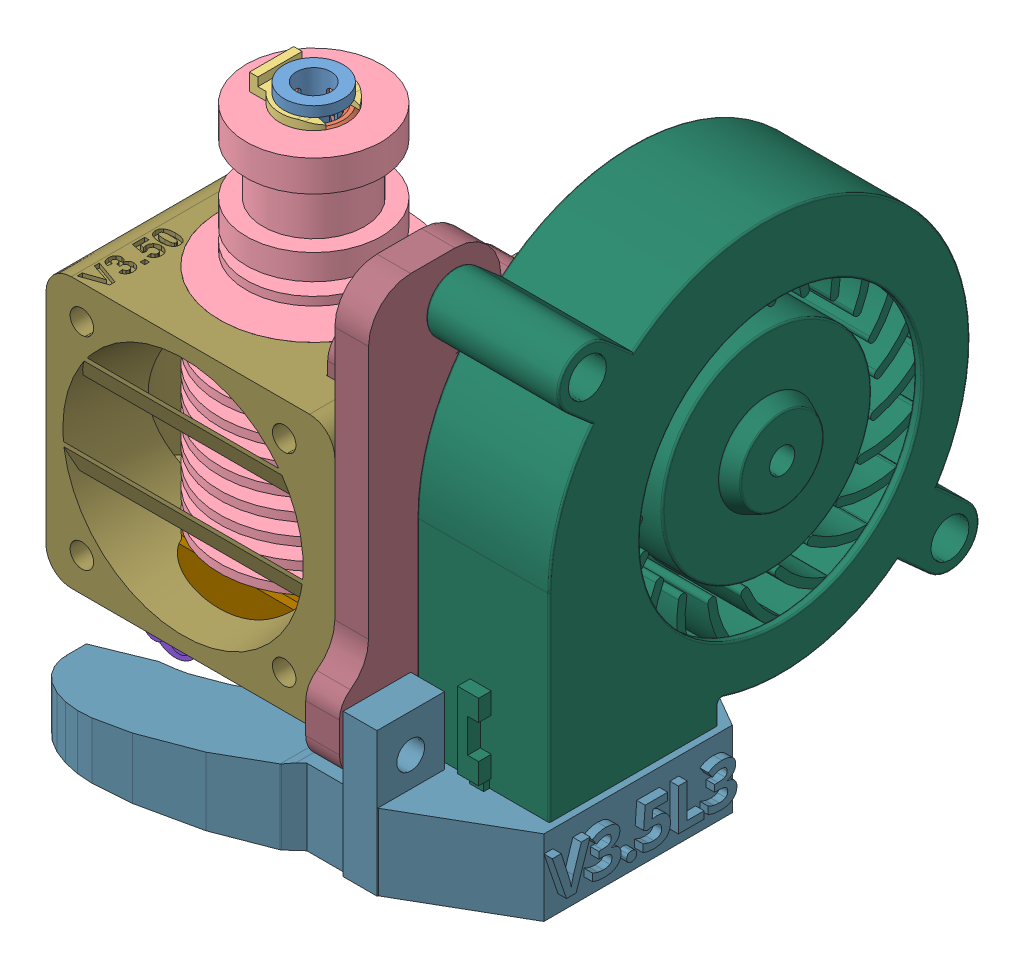
SolidWorks assembly large_blower_fan, configuration Default. Lengths in mm.
Overall size (55.78 64.5 67.05).
27 component instances, 18 part files, 12 mates.
Components (placement in the parent):
- e3D V6 1.75mm Hotend Assembly Mockup-1: e3D V6 1.75mm Hotend Assembly Mockup [Default] at (30.2552 8.4849 46.5447) x (1 0 0) z (0 1 0) size (38.97 30.07 64.5)
  - e3D V6 1.75mm Hotend Assembly Mockup.step-1: e3D V6 1.75mm Hotend Assembly Mockup.step [Default] at origin size (38.97 30.07 64.5)
    - V6-175-SINK.step-1: V6-175-SINK.step [Default] at (-0.0711 0 18.6) x (1 0.000031 0) z (0 0 1) size (22.3 22.3 44.95)
      - PTFE Tube Retainer.step-1: PTFE Tube Retainer.step [Default] at (0 0 1) x (-0.000024 -1 0) z (0 0 1) size (8 9 6.78)
        - Collet.step-1: Collet.step [Default] at (0 0 43.9) x (0 1 0) z (0 0 1) size (7 7 6.78)
        - Coupling.step-1: Coupling.step [Default] at (0 0 41.7) x (-0.000024 1 0) z (0 0 1) size (8 8 3.48)
        - Collet Clip.step-1: Collet Clip.step [Default] at (0 0 41.7) size (8 8.46 2)
      - V6-175-SINK-0.step-1: V6-175-SINK-0.step [Default] at origin size (22.3 22.3 42.75)
    - V6-Heatblock.step-1: V6-Heatblock.step [Default] at (-0.071 0.0711 5) x (1 0.000009 0) z (0 0 1) size (24.2 21 13.2)
      - M3x10 rounded head screw - 92095A182 (1).step-1: M3x10 rounded head screw - 92095A182 (1).step [Default] at (-12.5025 0 -1.6476) x (0.335243 0.942132 0) z (0 0 -1) size (5.7 5.7 11.65)
      - M3x4 flat tip set screw - 92605A098.step-1: M3x4 flat tip set screw - 92605A098.step [Default] at (6.0115 0 2.0029) x (-1 0.000002 0) z (0 0 -1) size (4.15 4.13 4)
      - Thermistor.step-1: Thermistor.step [Default] at (-0.0065 -2.7408 13.5951) x (1 0 0.000823) z (-0.000823 0 1) size (3 13.5 3)
      - Heater Cartridge.step-1: Heater Cartridge.step [Default] at (0.0988 0 0.1652) x (0.999682 0 0.025219) z (-0.025219 0 0.999682) size (5.9 21 5.9)
      - V6-Heatblock-1.step-1: V6-Heatblock-1.step [Default] at origin size (23 16 11.6)
    - Fan Assembly.step-1: Fan Assembly.step [Default] at (0 -26 15) size (33.65 30.07 30.1) (hidden)
      - Fan Shroud.step-1: Fan Shroud.step [Default] at (-16.2408 26 3.6) x (0 -1 0) z (0 0 1) size (30.07 22.05 30.1)
      - 30x10mm box fan.step-1: 30x10mm box fan.step [Default] at (-26.2408 26 18.6) x (0 -1 0) z (0 0 1) size (30 10 30)
      - M3x16 rounded head screw - 92095A184.step-1: M3x16 rounded head screw - 92095A184.step [Default] at (-27.8908 14 6.6) x (0 -1 0) z (-1 0 0) size (5.7 5.7 17.65)
      - M3x16 rounded head screw - 92095A184.step-2: M3x16 rounded head screw - 92095A184.step [Default] at (-27.8908 38 6.6) x (0 0 -1) z (-1 0 0) size (5.7 5.7 17.65)
      - M3x16 rounded head screw - 92095A184.step-3: M3x16 rounded head screw - 92095A184.step [Default] at (-27.8908 38 30.6) x (0 1 0) z (-1 0 0) size (5.7 5.7 17.65)
      - M3x16 rounded head screw - 92095A184.step-4: M3x16 rounded head screw - 92095A184.step [Default] at (-27.8908 14 30.6) x (0 0 1) z (-1 0 0) size (5.7 5.7 17.65)
    - V6-Heatbreak.step-1: V6-Heatbreak.step [Default] at (-0.071 0.0711 11.5) x (-1 -0.000034 0) z (0 0 1) size (6.99 6.98 22.15)
    - V6-175-Nozzle 0.4mm.step-1: V6-175-Nozzle 0.4mm.step [Default] at (-0.071 0.0711 1) x (1 0.000007 0) z (0 0 1) size (8.08 7 12.55)
- fan_clip-1: fan_clip [Default] at (-3.8159 22.0849 46.545) x (0.000009 0 1) z (0 1 0) size (32 34.3 32.03)
- blower_mount-1: blower_mount [Default] at (91.1843 4.528 68.6993) x (1 0 -0.000009) z (0 1 0) size (9.85 62.2 48.95)
- duct-1: duct [Default] at (16.6841 63.6337 46.5448) x (0.000009 0 1) z (0 1 0) size (47.6 51 17)
- Fan blower B5015E24B-1: Fan blower B5015E24B [Default] at (52.1839 43.0849 28.7945) x (0 -1 0) z (1 0 -0.000009) size (50.94 52.45 15.8)
Mates (geometry in assembly coordinates):
- Coincident1: coincident aligned: plane of e3D V6 1.75mm Hotend Assembly Mockup-1/e3D V6 1.75mm Hotend Assembly Mockup.step-1/V6-175-SINK.step-1/V6-175-SINK-0.step-1 through (30.1841 53.0849 46.5447) normal (0 1 0); plane of fan_clip-1 through (30.1841 53.0849 46.0447) normal (0 1 0)
- Concentric1: concentric aligned: circle of e3D V6 1.75mm Hotend Assembly Mockup-1/e3D V6 1.75mm Hotend Assembly Mockup.step-1/V6-175-SINK.step-1/V6-175-SINK-0.step-1; circle of fan_clip-1
- Parallel2: parallel aligned: plane of e3D V6 1.75mm Hotend Assembly Mockup-1/e3D V6 1.75mm Hotend Assembly Mockup.step-1/V6-Heatblock.step-1/V6-Heatblock-1.step-1 through (15.184 13.4849 38.4738) normal (-1 0 0.000009); plane of fan_clip-1 through (13.9342 22.0849 62.0448) normal (-1 0 0.000009)
- Width1: width aligned: plane of blower_mount-1 through (52.184 40.3349 36.6445) normal (-0.000009 0 -1); plane of fan_clip-1 through (52.1842 53.8599 57.0445) normal (0.000009 0 1); plane of blower_mount-1 through (48.1842 63.0849 57.0445) normal (-0.000009 0 -1); plane of fan_clip-1 through (48.184 30.5849 36.6445) normal (0.000009 0 1)
- Concentric2: concentric aligned: cylinder of fan_clip-1 through (45.184 50.0849 38.0446) axis (0.000009 0 1) radius 3; cylinder of blower_mount-1 through (45.1842 50.0849 57.0466) axis (0.000009 0 1) radius 3
- Coincident5: coincident anti-aligned: plane of fan_clip-1 through (48.1839 22.0849 30.0445) normal (1 0 -0.000009); plane of blower_mount-1 through (48.184 44.0599 34.3945) normal (-1 0 0.000009)
- Parallel3: parallel aligned: plane of blower_mount-1 through (47.2592 57.6349 57.0466) normal (0 1 0); plane of duct-1 through (47.3153 19.5849 46.5446) normal (0 1 0)
- Concentric3: concentric aligned: circle of blower_mount-1; circle of duct-1
- Coincident6: coincident anti-aligned: plane of blower_mount-1 through (52.184 44.0599 34.3945) normal (1 0 -0.000009); plane of duct-1 through (52.1842 10.5849 57.0445) normal (-1 0 0.000009)
- Concentric4: concentric aligned: circle of blower_mount-1; cylinder of Fan blower B5015E24B-1 through (52.1838 25.0849 8.7945) axis (1 0 -0.000009) radius 2.25
- Coincident7: coincident anti-aligned: plane of blower_mount-1 through (52.184 44.0599 34.3945) normal (1 0 -0.000009); plane of Fan blower B5015E24B-1 through (52.184 43.1573 30.8195) normal (-1 0 0.000009)
- Parallel4: parallel anti-aligned: plane of duct-1 through (57.1842 10.5849 57.0445) normal (-0.000009 0 -1); plane of Fan blower B5015E24B-1 through (52.1842 43.0849 56.2945) normal (0.000009 0 1)
